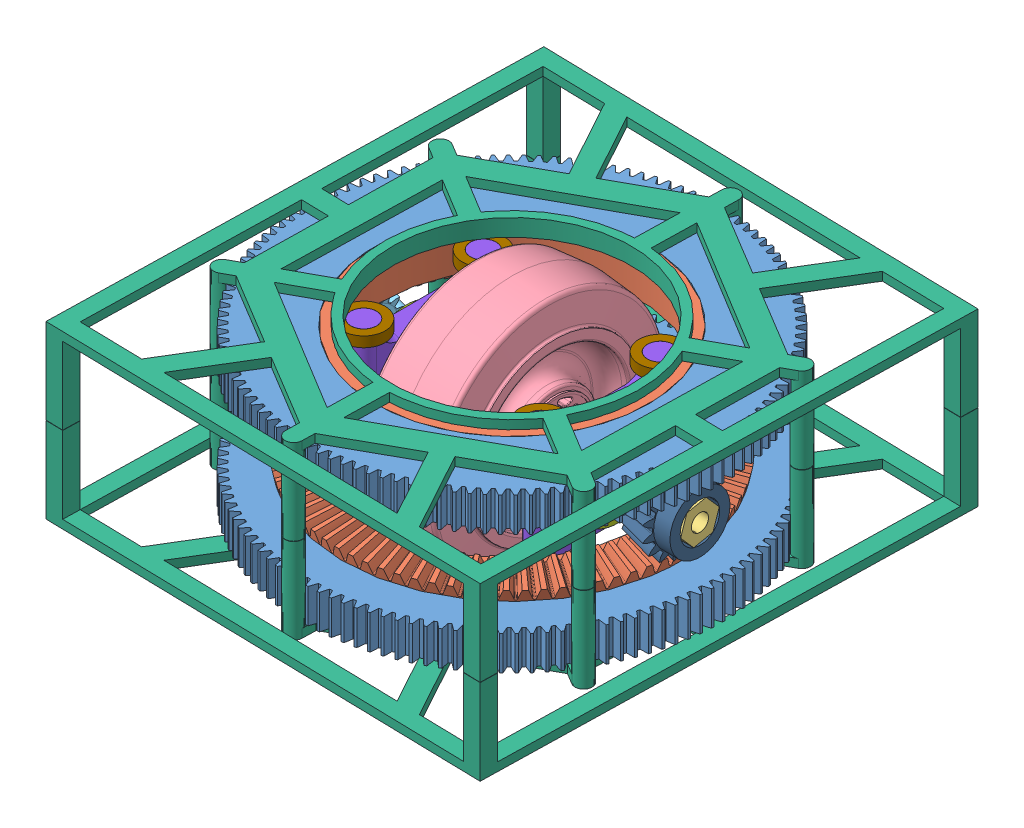
SolidWorks assembly Swerve Drive Assembly, configuration Default. Lengths in mm.
Overall size (219.44 226.59 219.44).
28 component instances, 10 part files, 40 mates.
Components (placement in the parent):
- Swerve Drive Spur-Bevel Sub_Assembly-1: Swerve Drive Spur-Bevel Sub_Assembly [Default] at (-66.3817 32.0196 63.8709) x (-0.45728 0.879047 0.134801) z (0.837032 0.476629 -0.268704) size (105.83 200.36 182.51)
  - spur gear_ai2-1: spur gear_ai2 [Inch - Spur gear 20DP 120T 20PA 0.5FW ---S120N3.0H2.0L4.0N] at (-67.1116 -41.2933 57.4645) x (0.879047 0.01004 0.476629) z (-0.447957 0.3595 0.818593) size (12.7 154.91 154.91)
  - straight bevel gear_ai2-1: straight bevel gear_ai2 [Inch - Straight bevel gear 16DP 80GT 16PT 20PA 0.5FW ---80O4H1.00MD3.75N] at (-55.9477 -41.1658 63.5177) x (0.879047 0.01004 0.476629) z (-0.447957 0.3595 0.818593) size (19.23 127.35 127.35)
- Swerve Drive Spur-Bevel Sub_Assembly-2: Swerve Drive Spur-Bevel Sub_Assembly [Default] at (84.3318 25.2468 -37.0697) x (0.298727 -0.879047 -0.371535) z (-0.56711 -0.476629 0.671722) size (105.83 200.36 182.51)
  - spur gear_ai2-1: spur gear_ai2 [Inch - Spur gear 20DP 120T 20PA 0.5FW ---S120N3.0H2.0L4.0N] at (-67.1116 -41.2933 57.4645) x (0.879047 0.01004 0.476629) z (-0.447957 0.3595 0.818593) size (12.7 154.91 154.91)
  - straight bevel gear_ai2-1: straight bevel gear_ai2 [Inch - Straight bevel gear 16DP 80GT 16PT 20PA 0.5FW ---80O4H1.00MD3.75N] at (-55.9477 -41.1658 63.5177) x (0.879047 0.01004 0.476629) z (-0.447957 0.3595 0.818593) size (19.23 127.35 127.35)
- Swerve Drive Axle-1: Swerve Drive Axle [Default] at (-0.0001 28.6332 0) x (0 -0.975978 -0.217869) z (-1 0 0) size (12.83 14.66 139.7)
- Swerve Drive 3.5in Colson Wheels-1: Swerve Drive 3.5in Colson Wheels [Default] at (-0.0065 28.6332 0) x (1 0 0) z (0 -0.748113 -0.663571) size (33.1 88.9 88.9)
- straight bevel pinion_ai3-1: straight bevel pinion_ai3 [Inch - Straight bevel pinion 16DP16PT 80GT 20PA .5FW ---16O1.25H2.75MD0.5N] at (-63.8029 28.6332 0) x (1 0 0) z (0 0.265184 0.964198) size (20.32 29 29)
- Swerve Drive Enclosure-1: Swerve Drive Enclosure [Default] at (0 57.2664 0) x (0.999744 0 0.022608) z (0 1 0) size (165.1 180.97 31.75)
- Swerve Drive Enclosure-2: Swerve Drive Enclosure [Default] x (0.999744 0 0.022608) z (0 -1 0) size (165.1 180.97 31.75)
- Swerve Drive Bearings-3: Swerve Drive Bearings [Default] at (31.2933 28.6332 0) x (0 0.748113 0.663571) z (0 0.663571 -0.748113) size (31.12 7.94 31.12)
- Swerve Drive Bearings-4: Swerve Drive Bearings [Default] at (34.4683 28.6332 0) x (0 0.200613 -0.979671) z (0 0.979671 0.200613) size (31.12 7.94 31.12)
- Swerve Drive Bearing Assembly-4: Swerve Drive Bearing Assembly [Default] at (-43.8505 49.5667 23.0188) x (0.235484 -0.559692 -0.794539) z (0.875467 -0.232841 0.423488) size (79.96 70.1 49.88)
  - Swerve Drive Bearing Mount-1: Swerve Drive Bearing Mount [Default] at (48.0747 25.7505 62.3017) x (-0.794539 -0.435162 0.423488) z (0.559692 -0.795318 0.232841) size (53.98 9.53 50.8)
  - Swerve Drive Bearing Mobilizer-1: Swerve Drive Bearing Mobilizer [Default] at (51.5171 55.6231 46.9755) x (0.426534 0.035574 -0.903772) z (-0.710502 -0.605148 -0.359141) size (15.88 3.81 15.88)
  - Swerve Drive Bearing Mobilizer-2: Swerve Drive Bearing Mobilizer [Default] at (16.1998 36.2801 65.7996) x (-0.080169 -0.331617 -0.940002) z (-0.824814 -0.507445 0.249363) size (15.88 3.81 15.88)
  - Swerve Drive Bearing Mobilizer-3: Swerve Drive Bearing Mobilizer [Default] at (77.817 18.2511 57.9167) x (0.426534 0.035574 -0.903772) z (-0.710502 -0.605148 -0.359141) size (15.88 3.81 15.88)
  - Swerve Drive Bearing Mobilizer-4: Swerve Drive Bearing Mobilizer [Default] at (42.4998 -1.0919 76.7408) x (0.307977 -0.061223 -0.949422) z (-0.769347 -0.603094 -0.210673) size (15.88 3.81 15.88)
- Swerve Drive Bearings-5: Swerve Drive Bearings [Default] at (-34.4683 28.6332 0) x (0 -0.948726 0.316099) z (0 0.316099 0.948726) size (31.12 7.94 31.12)
- Swerve Drive Bearings-6: Swerve Drive Bearings [Default] at (-31.2933 28.6332 0) x (0 0.748113 0.663571) z (0 -0.663571 0.748113) size (31.12 7.94 31.12)
- Swerve Drive Bearing Assembly-5: Swerve Drive Bearing Assembly [Default] at (-109.6121 49.5667 23.0188) x (0.235484 -0.559692 -0.794539) z (0.875467 -0.232841 0.423488) size (79.96 70.1 49.88)
  - Swerve Drive Bearing Mount-1: Swerve Drive Bearing Mount [Default] at (48.0747 25.7505 62.3017) x (-0.794539 -0.435162 0.423488) z (0.559692 -0.795318 0.232841) size (53.98 9.53 50.8)
  - Swerve Drive Bearing Mobilizer-1: Swerve Drive Bearing Mobilizer [Default] at (51.5171 55.6231 46.9755) x (0.426534 0.035574 -0.903772) z (-0.710502 -0.605148 -0.359141) size (15.88 3.81 15.88)
  - Swerve Drive Bearing Mobilizer-2: Swerve Drive Bearing Mobilizer [Default] at (16.1998 36.2801 65.7996) x (-0.080169 -0.331617 -0.940002) z (-0.824814 -0.507445 0.249363) size (15.88 3.81 15.88)
  - Swerve Drive Bearing Mobilizer-3: Swerve Drive Bearing Mobilizer [Default] at (77.817 18.2511 57.9167) x (0.426534 0.035574 -0.903772) z (-0.710502 -0.605148 -0.359141) size (15.88 3.81 15.88)
  - Swerve Drive Bearing Mobilizer-4: Swerve Drive Bearing Mobilizer [Default] at (42.4998 -1.0919 76.7408) x (0.307977 -0.061223 -0.949422) z (-0.769347 -0.603094 -0.210673) size (15.88 3.81 15.88)
- straight bevel pinion_ai5-4: straight bevel pinion_ai5 [Inch - Straight bevel pinion 16DP16PT 80GT 20PA .5FW ---16O1.25H2.75MD0.5N] at (63.8027 28.6332 0) x (-1 0 0) z (0 0.924225 0.381849) size (20.32 29 29)
Mates (geometry in assembly coordinates):
- Coincident1: coincident anti-aligned: plane of Swerve Drive Spur-Bevel Sub_Assembly-1/spur gear_ai2-1 through (0 0 0) normal (0 -1 0); plane of assembly through (0 0 0) normal (0 1 0)
- Concentric1: concentric: cylinder of Swerve Drive Spur-Bevel Sub_Assembly-1/straight bevel gear_ai2-1 through (0 38.1001 0) axis (0 -1 0) radius 47.625; point of assembly
- Parallel2: parallel anti-aligned: plane of Swerve Drive Spur-Bevel Sub_Assembly-1/spur gear_ai2-1 through (0 12.7 0) normal (0 1 0); plane of Swerve Drive Spur-Bevel Sub_Assembly-2/spur gear_ai2-1 through (0 44.5664 0) normal (0 -1 0)
- Coincident29: coincident: point of Swerve Drive Spur-Bevel Sub_Assembly-1/straight bevel gear_ai2-1; point of Swerve Drive Spur-Bevel Sub_Assembly-2/straight bevel gear_ai2-1
- Parallel3: parallel aligned: plane of Swerve Drive Axle-1 through (69.8499 27.1622 7.1833) normal (0 0.316099 0.948726); plane of Swerve Drive 3.5in Colson Wheels-1 through (-16.2561 30.1002 -7.1953) normal (0 0.316099 0.948726)
- Coincident30: coincident: point of Swerve Drive Spur-Bevel Sub_Assembly-1/straight bevel gear_ai2-1; point of straight bevel pinion_ai3-1
- Perpendicular1: perpendicular: line of Swerve Drive Spur-Bevel Sub_Assembly-2/straight bevel gear_ai2-1 through (0 54.5664 0) axis (0 -1 0); line of straight bevel pinion_ai3-1 through (-73.8029 28.6332 0) axis (1 0 0)
- Coincident32: coincident: line of straight bevel pinion_ai3-1 through (-73.8029 28.6332 0) axis (1 0 0); plane of assembly
- Concentric2: concentric anti-aligned: cylinder of Swerve Drive Axle-1 through (69.8499 28.6332 0) axis (-1 0 0) radius 3.175; cylinder of straight bevel pinion_ai3-1 through (-69.8501 28.6332 0) axis (1 0 0) radius 11.1854
- Coincident34: coincident anti-aligned: plane of Swerve Drive Axle-1 through (69.8499 23.1478 -4.8655) normal (0 -0.979671 -0.200613); plane of straight bevel pinion_ai3-1 through (6.0471 21.6768 2.3177) normal (0 0.979671 0.200613)
- Coincident35: coincident aligned: plane of Swerve Drive Axle-1 through (-69.8501 28.6332 0) normal (-1 0 0); plane of straight bevel pinion_ai3-1 through (-69.8501 28.6332 0) normal (-1 0 0)
- Distance1: distance = 53.594 mm aligned: plane of Swerve Drive 3.5in Colson Wheels-1 through (-16.2561 28.6332 0) normal (-1 0 0); plane of Swerve Drive Axle-1 through (-69.8501 28.6332 0) normal (-1 0 0)
- Concentric4: concentric anti-aligned: cylinder of Swerve Drive Axle-1 through (69.8499 28.6332 0) axis (-1 0 0) radius 3.175; circle of Swerve Drive 3.5in Colson Wheels-1
- Coincident38: coincident anti-aligned: plane of Swerve Drive Spur-Bevel Sub_Assembly-2/spur gear_ai2-1 through (0 57.2664 0) normal (0 1 0); plane of Swerve Drive Enclosure-1 through (0 57.2664 0) normal (0 -1 0)
- Coincident39: coincident anti-aligned: plane of Swerve Drive Spur-Bevel Sub_Assembly-1/spur gear_ai2-1 through (0 0 0) normal (0 -1 0); plane of Swerve Drive Enclosure-2 through (0 0 0) normal (0 1 0)
- Coincident40: coincident aligned: plane of Swerve Drive Axle-1 through (-69.8501 28.6332 0) normal (-1 0 0); plane of straight bevel pinion_ai3-1 through (-69.8501 28.6332 0) normal (-1 0 0)
- Parallel13: parallel aligned: plane of Swerve Drive Enclosure-1 through (0 57.2664 0) normal (0 -1 0); plane of Swerve Drive Enclosure-2 through (0 -3.175 0) normal (0 -1 0)
- Concentric19: concentric anti-aligned: cylinder of Swerve Drive Enclosure-1 through (0 54.0914 0) axis (0 1 0) radius 44.45; cylinder of Swerve Drive Enclosure-2 through (0 3.175 0) axis (0 -1 0) radius 44.45
- Coincident60: coincident aligned: plane of Swerve Drive Enclosure-1 through (-82.5289 60.4414 -1.8663) normal (-0.999744 0 -0.022608); plane of Swerve Drive Enclosure-2 through (-82.5289 -3.175 -1.8663) normal (-0.999744 0 -0.022608)
- Concentric20: concentric aligned: cylinder of Swerve Drive Spur-Bevel Sub_Assembly-1/straight bevel gear_ai2-1 through (0 38.1001 0) axis (0 -1 0) radius 47.625; cylinder of Swerve Drive Enclosure-2 through (0 3.175 0) axis (0 -1 0) radius 44.45
- Concentric22: concentric anti-aligned: cylinder of Swerve Drive Axle-1 through (69.8499 28.6332 0) axis (-1 0 0) radius 3.175; cylinder of Swerve Drive Bearings-3 through (31.2933 28.6332 0) axis (1 0 0) radius 14.2748
- Parallel18: parallel aligned: plane of Swerve Drive Axle-1 through (69.8499 23.1478 -4.8655) normal (0 -0.979671 -0.200613); plane of Swerve Drive Bearings-3 through (31.2933 35.6006 -2.3214) normal (0 -0.979671 -0.200613)
- Concentric23: concentric anti-aligned: cylinder of Swerve Drive Bearings-3 through (31.2933 28.6332 0) axis (1 0 0) radius 14.2748; cylinder of Swerve Drive Bearings-4 through (34.4683 28.6332 0) axis (-1 0 0) radius 14.2748
- Coincident64: coincident aligned: plane of Swerve Drive Bearings-3 through (31.2933 34.1273 4.8732) normal (0 -0.316099 -0.948726); plane of Swerve Drive Bearings-4 through (34.4683 27.1599 7.1946) normal (0 -0.316099 -0.948726)
- Concentric24: concentric anti-aligned: cylinder of Swerve Drive Bearings-4 through (34.4683 28.6332 0) axis (-1 0 0) radius 14.2748; cylinder of Swerve Drive Bearing Assembly-4/Swerve Drive Bearing Mount-1 through (16.3708 28.6332 0) axis (1 0 0) radius 14.224
- Coincident65: coincident anti-aligned: plane of Swerve Drive Bearings-4 through (28.1183 31.7542 -15.2412) normal (1 0 0); plane of Swerve Drive Bearing Assembly-4/Swerve Drive Bearing Mount-1 through (28.1183 45.1432 0) normal (-1 0 0)
- Coincident66: coincident anti-aligned: plane of Swerve Drive Bearings-3 through (37.6433 40.272 10.3235) normal (-1 0 0); plane of Swerve Drive Bearing Assembly-4/Swerve Drive Bearing Mount-1 through (37.6433 45.1432 0) normal (1 0 0)
- Parallel19: parallel aligned: plane of Swerve Drive Enclosure-1 through (0 60.4414 0) normal (0 1 0); plane of Swerve Drive Bearing Assembly-4/Swerve Drive Bearing Mount-1 through (32.8808 45.1432 0) normal (0 1 0)
- Tangent6: tangent aligned: cylinder of Swerve Drive Spur-Bevel Sub_Assembly-2/straight bevel gear_ai2-1 through (0 19.1664 0) axis (0 1 0) radius 47.625; cylinder of Swerve Drive Bearing Assembly-4/Swerve Drive Bearing Mobilizer-1 through (32.8808 50.2232 -22.225) axis (0 1 0) radius 7.9375
- Concentric26: concentric anti-aligned: cylinder of Swerve Drive Axle-1 through (69.8499 28.6332 0) axis (-1 0 0) radius 3.175; cylinder of Swerve Drive Bearings-5 through (-34.4683 28.6332 0) axis (1 0 0) radius 14.2748
- Parallel21: parallel aligned: plane of Swerve Drive Axle-1 through (69.8499 27.1622 7.1833) normal (0 0.316099 0.948726); plane of Swerve Drive Bearings-5 through (-34.4683 23.1391 -4.8732) normal (0 0.316099 0.948726)
- Concentric27: concentric anti-aligned: cylinder of Swerve Drive Bearings-5 through (-34.4683 28.6332 0) axis (1 0 0) radius 14.2748; cylinder of Swerve Drive Bearings-6 through (-31.2933 28.6332 0) axis (-1 0 0) radius 14.2748
- Parallel22: parallel aligned: plane of Swerve Drive Bearings-5 through (-34.4683 23.1391 -4.8732) normal (0 0.316099 0.948726); plane of Swerve Drive Bearings-6 through (-31.2933 30.1065 -7.1946) normal (0 0.316099 0.948726)
- Parallel23: parallel aligned: plane of Swerve Drive Enclosure-1 through (0 60.4414 0) normal (0 1 0); plane of Swerve Drive Bearing Assembly-5/Swerve Drive Bearing Mount-1 through (-32.8808 45.1432 0) normal (0 1 0)
- Coincident71: coincident anti-aligned: plane of Swerve Drive Bearings-6 through (-37.6433 40.272 10.3235) normal (1 0 0); plane of Swerve Drive Bearing Assembly-5/Swerve Drive Bearing Mount-1 through (-37.6433 45.1432 0) normal (-1 0 0)
- Concentric28: concentric aligned: cylinder of Swerve Drive Bearings-5 through (-34.4683 28.6332 0) axis (1 0 0) radius 14.2748; cylinder of Swerve Drive Bearing Assembly-5/Swerve Drive Bearing Mount-1 through (-49.3908 28.6332 0) axis (1 0 0) radius 14.224
- Coincident72: coincident anti-aligned: plane of Swerve Drive Bearings-5 through (-28.1183 13.8734 4.9177) normal (-1 0 0); plane of Swerve Drive Bearing Assembly-5/Swerve Drive Bearing Mount-1 through (-28.1183 45.1432 0) normal (1 0 0)
- Tangent7: tangent aligned: cylinder of Swerve Drive Spur-Bevel Sub_Assembly-2/straight bevel gear_ai2-1 through (0 19.1664 0) axis (0 1 0) radius 47.625; cylinder of Swerve Drive Bearing Assembly-5/Swerve Drive Bearing Mobilizer-1 through (-32.8808 50.2232 -22.225) axis (0 1 0) radius 7.9375
- Coincident75: coincident: plane of Swerve Drive Axle-1 through (69.8499 28.6332 0) normal (1 0 0); plane of straight bevel pinion_ai5-4 through (69.8499 28.6332 0) normal (1 0 0)
- Concentric35: concentric: cylinder of Swerve Drive Axle-1 through (69.8499 28.6332 0) axis (-1 0 0) radius 3.175; cylinder of straight bevel pinion_ai5-4 through (49.0707 28.6332 0) axis (1 0 0) radius 7.366
